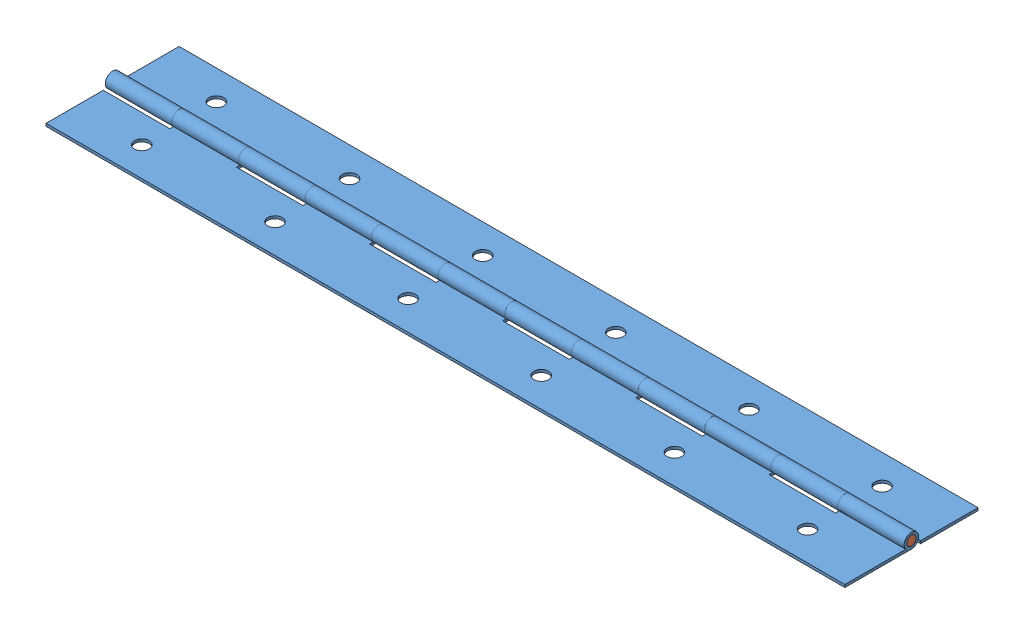
SolidWorks assembly GE-20344, configuration Default. Lengths in mm.
Overall size (304.8 5.59 50.8).
3 component instances, 2 part files, 4 mates.
Components (placement in the parent):
- GE-20344-01-3: GE-20344-01 [Default] at (644.0434 1017.743 1392.3753) size (304.8 5.59 28.19)
- GE-20344-01-4: GE-20344-01 [Default] at (644.0434 1017.743 1392.3753) x (-1 0 0) z (0 0 -1) size (304.8 5.59 28.19)
- GE-20344-02-1: GE-20344-02 [Default] at (644.0434 1017.743 1392.3753) size (304.8 3.56 3.56)
Mates (geometry in assembly coordinates):
- Coincident1: coincident anti-aligned: plane of GE-20344-01-3 through (644.0434 1017.743 1392.3753) normal (1 0 0); plane of GE-20344-01-4 through (644.0434 1017.743 1392.3753) normal (-1 0 0)
- Concentric1: concentric anti-aligned: cylinder of GE-20344-01-3 through (796.4434 1017.743 1392.3753) axis (-1 0 0) radius 2.794; cylinder of GE-20344-01-4 through (491.6434 1017.743 1392.3753) axis (1 0 0) radius 2.794
- Coincident2: coincident aligned: plane of GE-20344-01-3 through (644.0434 1017.743 1392.3753) normal (1 0 0); plane of Hinge-025-1 through (644.0434 1017.743 1392.3753) normal (1 0 0)
- Concentric2: concentric anti-aligned: cylinder of GE-20344-01-4 through (491.6434 1017.743 1392.3753) axis (1 0 0) radius 2.794; cylinder of Hinge-025-1 through (796.4434 1017.743 1392.3753) axis (-1 0 0) radius 1.778
